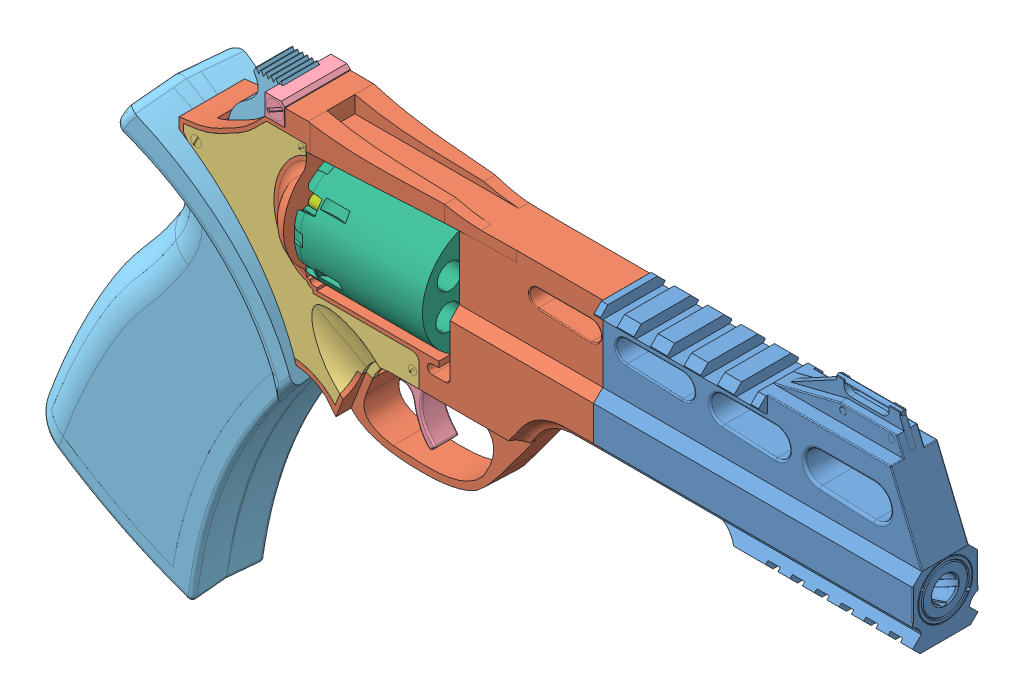
SolidWorks assembly Assem3(.36_Rifled), configuration Default. Lengths in mm.
Overall size (319.33 178.36 45.01).
33 component instances, 25 part files, 51 mates.
Components (placement in the parent):
- Part-1(.36_Rifled)-1: Part-1(.36_Rifled) [Default] at (11.9965 32.6768 113.9743) size (117.72 64.57 23.76)
- Part-2b(.36_Rifled)-3: Part-2b(.36_Rifled) [Default] at (-21.7434 30.6863 114.078) size (166.02 109.03 43.02)
- Comp-2: Comp [Default] at (-13.7813 33.0136 111.9172) size (95.88 46.02 19.79)
- TRigger-2: TRigger [Default] at (-1308.0404 -1190.4474 118.8218) x (0.981914 0.189327 0) z (0 0 1) size (23.19 35.38 9.97)
- Hammer-2: Hammer [Default] at (-35.5126 36.5966 114.1094) size (26.46 31.09 13.23)
- Roller-1-3: Roller-1 [Default] at (-3.9075 114.1625 112.9787) x (0.74655 -0.66533 0) z (0 0 1) size (8.89 8.89 7.11)
- Spring-1: Spring [Default] at (-17.4358 57.0675 123.8361) x (0.998565 -0.053556 0) z (0 0 1) size (17.15 30.92 6.73)
- Roller-1-4: Roller-1 [Default] at (-10.8089 88.3962 113.0344) x (0.941065 0.338225 0) z (0 0 1) size (8.89 8.89 7.11)
- Sylinder Stop Level-1: Sylinder Stop Level [Default] at (56.163 93.2048 121.6948) x (0.99736 -0.072616 0) z (0 0 1) size (15.92 19.29 0.76)
- Level-1-1: Level-1 [Default] at (0.1659 -0.0827 121.6948) size (14.49 13.67 2.03)
- Single Action Level-1: Single Action Level [Default] at (0 0 122.4568) size (15.63 8.34 0.76)
- Level-2-1: Level-2 [Default] at (45.7184 96.0003 120.9328) x (0.995526 0.094487 0) z (0 0 1) size (10.88 7.58 0.76)
- Washer-1: Washer [Default] at (0 0 123.2188) size (5.59 5.59 0.38)
- Interlink Level-1: Interlink Level [Default] at (1.5397 0.4861 120.1708) size (15.02 13.6 0.76)
- Level-3-2: Level-3 [Default] at (0 0 120.1708) size (27.43 20.24 0.76)
- Washer-2: Washer [Default] at (-55.7165 15.1252 120.9328) x (0.911643 -0.410984 0) z (0 0 1) size (5.59 5.59 0.38)
- Return Level-1-2: Return Level-1 [Default] at (0.2327 -0.0811 120.1464) size (29.87 18 1.27)
- Cocking Lever-3: Cocking Lever [Default] at (-21.9432 31.6954 126.9544) x (0.999997 -0.002422 0) z (0 0 1) size (14.7 40.87 2.54)
- Level-4-1: Level-4 [Default] at (10.0529 99.6563 120.3544) size (32.56 44.92 0.76)
- Return level-a-1: Return level-a [Default] at (0 0 119.8924) size (24.34 19.46 0.76)
- Level-5-1: Level-5 [Default] at (-11.0551 3.7924 121.6604) x (0.990855 -0.134931 0) z (0 0 1) size (30.27 13.58 0.76)
- Washer-3: Washer [Default] at (-21.9488 -10.3949 122.4284) x (0.999916 -0.012965 0) z (0 0 1) size (5.59 5.59 0.38)
- Level-6-1: Level-6 [Default] at (13.6029 82.0165 121.078) size (23.07 16.41 0.76)
- Cap-1-8: Cap-1 [Default] at (-21.7434 30.6863 132.0844) size (100.11 99.36 7.94)
- Tab-1: Tab [Default] at (16.0588 150.9977 109.5944) size (7.11 7.62 23.88)
- Hand Grip-1: Hand Grip [Default] at (0 0 -0.116) size (97.91 152.5 40.37)
- Cylinder Smoothbore.36-1: Cylinder Smoothbore.36 [Default] at (-139.1664 -178.8195 173.3584) x (0.922784 0.385042 -0.014592) z (0 0.037869 0.999283) size (60.74 55.75 42.2)
- Nippel-2: Nippel [Default] at (-107.6697 -202.1553 178.7271) x (0.882314 0.458894 -0.104589) z (0.142896 -0.049453 0.988501) size (12.39 9.96 7.5)
- Nippel-3: Nippel [Default] at (-107.6697 9.7057 431.1756) x (0.882314 0.138871 -0.449708) z (0.142896 0.831341 0.537078) size (12.39 9.96 7.5)
- Nippel-4: Nippel [Default] at (-107.6697 334.263 373.9229) x (0.882314 -0.320023 -0.345119) z (0.142896 0.880794 -0.451423) size (12.39 9.96 7.5)
- Nippel-5: Nippel [Default] at (-107.6697 446.9593 64.2216) x (0.882314 -0.458894 0.104589) z (0.142896 0.049453 -0.988501) size (12.39 9.96 7.5)
- Nippel-6: Nippel [Default] at (-107.6697 235.0983 -188.2269) x (0.882314 -0.138871 0.449708) z (0.142896 -0.831341 -0.537078) size (12.39 9.96 7.5)
- Nippel-7: Nippel [Default] at (-107.6697 -89.459 -130.9741) x (0.882314 0.320023 0.345119) z (0.142896 -0.880794 0.451423) size (12.39 9.96 7.5)
Mates (geometry in assembly coordinates):
- Coincident2: coincident: point of Part-1(.36_Rifled)-1; plane of Part-2b(.36_Rifled)-3 through (131.8032 154.0143 107.9744) normal (1 0 0)
- Parallel1: parallel: plane of Part-1(.36_Rifled)-1 through (77.4665 119.7078 112.9694) normal (0 0.707107 -0.707107); plane of Part-2b(.36_Rifled)-3 through (77.4665 119.7078 112.9694) normal (0 0.707107 -0.707107)
- Coincident3: coincident: point of Part-1(.36_Rifled)-1; point of Part-2b(.36_Rifled)-3
- Lock1: lock: unknown of Part-1(.36_Rifled)-1
- Concentric5: concentric: cylinder of Part-2b(.36_Rifled)-3 through (83.4172 98.0287 114.7516) axis (1 0 0) radius 1.35; cylinder of Comp-2 through (84.7672 98.0287 114.7516) axis (1 0 0) radius 1.35
- Distance2: distance = 0 mm: plane of Comp-2 through (98.2672 89.6122 114.7244) normal (1 0 0); plane of Part-2b(.36_Rifled)-3 through (98.2672 89.6122 114.7244) normal (-1 0 0)
- Concentric9: concentric: cylinder of Part-2b(.36_Rifled)-3 through (58.9472 95.6799 132.3384) axis (0 0 -1) radius 1.397; cylinder of TRigger-2 through (58.9472 95.6799 126.1418) axis (0 0 -1) radius 1.3449
- Distance8: distance = 4.4674 mm: plane of TRigger-2 through (52.0713 88.8803 117.5018) normal (0 0 -1); plane of Part-2b(.36_Rifled)-3 through (-22.8364 81.2302 113.0344) normal (0 0 1)
- Parallel3: parallel: plane of Part-2b(.36_Rifled)-3 through (39.5363 590.2559 112.9694) normal (0 0 -1); plane of Comp-2 through (-50.365 2.3008 111.0794) normal (0 0 -1)
- Distance10: distance = 0 mm: plane of Hammer-2 through (4.401 147.8947 128.2244) normal (0 0 1); plane of Part-2b(.36_Rifled)-3 through (-50.365 2.3008 128.2244) normal (0 0 -1)
- Concentric11: concentric: cylinder of Part-2b(.36_Rifled)-3 through (12.3621 128.1839 125.7344) axis (0 0 -1) radius 1.905; cylinder of Hammer-2 through (12.3621 128.1839 114.9944) axis (0 0 1) radius 1.905
- Concentric13: concentric: cylinder of Part-2b(.36_Rifled)-3 through (-3.9075 114.1625 130.8144) axis (0 0 -1) radius 2.54; cylinder of Roller-1-3 through (-3.9075 114.1625 120.0907) axis (0 0 -1) radius 2.54
- Concentric15: concentric: circle of Part-2b(.36_Rifled)-3; circle of Spring-1
- Concentric16: concentric: cylinder of Part-2b(.36_Rifled)-3 through (-10.8089 88.3962 130.8144) axis (0 0 -1) radius 2.54; circle of Roller-1-4
- Concentric17: concentric: circle of TRigger-2; circle of Sylinder Stop Level-1
- Distance14: distance = 0 mm: plane of Sylinder Stop Level-1 through (58.2796 93.0076 122.4568) normal (0 0 1); plane of TRigger-2 through (54.6141 85.4435 122.4568) normal (0 0 -1)
- Concentric18: concentric: circle of Part-2b(.36_Rifled)-3; circle of Level-1-1
- Distance15: distance = 0 mm: plane of Level-1-1 through (43.1783 94.4157 122.4568) normal (0 0 1); plane of Sylinder Stop Level-1 through (58.2796 93.0076 122.4568) normal (0 0 1)
- Concentric19: concentric: circle of Part-2b(.36_Rifled)-3; circle of Single Action Level-1
- Distance16: distance = 0.762 mm: plane of Single Action Level-1 through (30.7873 97.2642 123.2188) normal (0 0 1); plane of Level-1-1 through (43.1783 94.4157 122.4568) normal (0 0 1)
- Concentric20: concentric: circle of Part-2b(.36_Rifled)-3; circle of Level-2-1
- Distance18: distance = 0 mm: plane of Level-2-1 through (47.7291 97.2373 121.6948) normal (0 0 1); line of Level-1-1 through (40.1894 94.4157 121.6948) axis (0.275021 -0.961438 0)
- Distance20: distance = 0.381 mm: plane of Washer-1 through (43.1783 94.4157 123.5998) normal (0 0 1); plane of Single Action Level-1 through (30.7873 97.2642 123.2188) normal (0 0 1)
- Concentric22: concentric: circle of Single Action Level-1; circle of Washer-1
- Distance21: distance = 1.524 mm: plane of Interlink Level-1 through (38.453 97.4027 120.9328) normal (0 0 1); plane of Level-1-1 through (43.1783 94.4157 122.4568) normal (0 0 1)
- Concentric24: concentric: cylinder of Part-2b(.36_Rifled)-3 through (22.45 83.453 136.2025) axis (0 0 -1) radius 1.905; circle of Level-3-2
- Distance23: distance = 0 mm: plane of Level-3-2 through (0 0 120.9328) normal (0 0 1); plane of Interlink Level-1 through (38.453 97.4027 120.9328) normal (0 0 1)
- Concentric25: concentric: circle of Part-2b(.36_Rifled)-3; circle of Washer-2
- Distance24: distance = 0.381 mm: plane of Washer-2 through (22.45 83.453 121.3138) normal (0 0 1); plane of Level-3-2 through (0 0 120.9328) normal (0 0 1)
- Concentric26: concentric: circle of Part-2b(.36_Rifled)-3; circle of Return Level-1-2
- Coincident4: coincident: plane of Part-2b(.36_Rifled)-3 through (-22.8364 81.2302 113.0344) normal (0 0 1); circle of Roller-1-4
- Distance28: distance = 0 mm: line of Return Level-1-2 through (-14.6189 88.3962 120.1464) axis (0.133316 -0.991074 0); plane of Roller-1-4 through (-10.8089 88.3962 120.1464) normal (0 0 1)
- Tangent2: tangent: cylinder of Part-2b(.36_Rifled)-3 through (-3.9075 114.1625 130.8144) axis (0 0 -1) radius 2.54; plane of Cocking Lever-3 through (-6.484 99.0669 128.2244) normal (0.999997 -0.002422 0)
- Tangent3: tangent: cylinder of Part-2b(.36_Rifled)-3 through (-3.9075 114.1625 130.8144) axis (0 0 -1) radius 2.54; line of Cocking Lever-3 through (-1.4176 93.4614 128.2244) axis (0.002422 0.999997 0)
- Coincident6: coincident: plane of Hammer-2 through (14.9228 117.1256 125.6844) normal (0 0 1); circle of Cocking Lever-3
- Distance30: distance = 0.762 mm: plane of Level-4-1 through (20.4747 82.9847 120.6544) normal (0 0 1); plane of Return Level-1-2 through (-10.8089 88.3962 121.4164) normal (0 0 1)
- Concentric27: concentric: circle of Part-2b(.36_Rifled)-3; circle of Return level-a-1
- Distance32: distance = 0.762 mm: plane of Return level-a-1 through (-10.141 81.0427 120.6544) normal (0 0 1); plane of Return Level-1-2 through (-10.8089 88.3962 121.4164) normal (0 0 1)
- Concentric28: concentric: circle of Part-2b(.36_Rifled)-3; circle of Level-5-1
- Concentric30: concentric: cylinder of Part-2b(.36_Rifled)-3 through (22.45 83.453 136.2025) axis (0 0 -1) radius 1.905; circle of Washer-3
- Concentric31: concentric: circle of Part-2b(.36_Rifled)-3; circle of Level-6-1
- Coincident9: coincident: point of Part-2b(.36_Rifled)-3; point of Cap-1-8
- Coincident10: coincident: point of Part-2b(.36_Rifled)-3; point of Tab-1
- Parallel7: parallel: plane of Cap-1-8 through (28.7542 75.0755 133.3544) normal (0 0 1); plane of Hand Grip-1 through (3.8929 66.6096 109.4784) normal (0 0 1)
- Coincident20: coincident: point of Part-2b(.36_Rifled)-3; point of Hand Grip-1
- Lock2: lock: unknown of Cap-1-8; unknown of Hand Grip-1
- Lock3: lock: unknown of Part-2b(.36_Rifled)-3; unknown of Cap-1-8
- Concentric32: concentric: cylinder of Comp-2 through (34.7672 122.402 121.4744) axis (1 0 0) radius 3.429; cylinder of Cylinder Smoothbore.36-1 through (52.8969 122.402 121.4744) axis (-1 0 0) radius 3.5
- Distance33: distance = 0 mm: plane of Part-2b(.36_Rifled)-3 through (27.3969 140.7319 137.1644) normal (1 0 0); plane of Cylinder Smoothbore.36-1 through (27.3969 110.5961 115.242) normal (-1 0 0)
- Concentric34: concentric: cylinder of Cylinder Smoothbore.36-1 through (29.8954 130.6455 134.58) axis (0.984808 -0.092457 -0.146988) radius 2.067; cylinder of Nippel-2 through (36.592 130.0168 133.5804) axis (-0.984808 0.092457 0.146988) radius 2.5
- Distance34: distance = 0 mm: plane of Nippel-2 through (37.9008 131.993 133.6223) normal (0.984808 -0.092457 -0.146988); plane of Cylinder Smoothbore.36-1 through (37.6753 131.6648 132.3182) normal (-0.984808 0.092457 0.146988)
